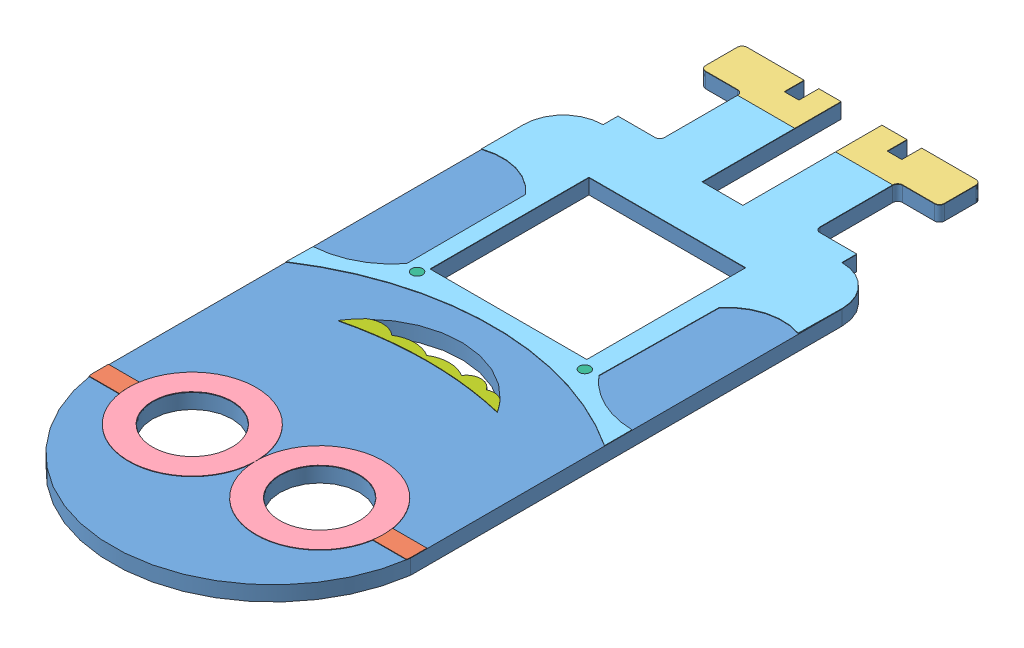
SolidWorks assembly Ensamblaje1, configuration Predeterminado. Lengths in mm.
Overall size (64.13 3.1 150.86).
7 component instances, 7 part files, 15 mates.
Components (placement in the parent):
- front-1: front [Predeterminado] at (-2.4657 43.7113 153.94) x (1 0 0) z (0 -1 0) size (64.13 150.86 3)
- band-1: band [Predeterminado] at (-62.549 43.8113 189.7256) x (1 0 0) z (0 -1 0) size (64.13 4 0.1)
- boots-1: boots [Predeterminado] at (-43.7181 43.8113 94.3) x (1 0 0) z (0 -1 0) size (48.08 9.33 0.1)
- eyes-1: eyes [Predeterminado] at (-37.429 43.7113 229.6833) x (1 0 0) z (0 1 0) size (51.31 25.65 0.1)
- jumpsuit-1: jumpsuit [Predeterminado] at (-44.951 43.8113 135.8861) x (1 0 0) z (0 -1 0) size (64.13 74.47 0.1)
- buttons-1: buttons [Predeterminado] at (-31.8965 43.8113 144.2405) x (1 0 0) z (0 -1 0) size (36.12 2.34 0.1)
- teeth-1: teeth [Predeterminado] at (-44.9051 43.8113 160.5398) x (1 0 0) z (0 -1 0) size (31.98 4.22 0.1)
Mates (geometry in assembly coordinates):
- Coincidente8: coincident: line of front-1 through (-41.4957 40.7113 214.3897) axis (0 1 0); line of band-1 through (-41.4957 43.7113 214.3897) axis (0 1 0)
- Coincidente10: coincident: plane of front-1 through (13.6183 43.7113 98.8397) normal (0 1 0); plane of band-1 through (-9.429 43.7113 209.9974) normal (0 -1 0)
- Coincidente11: coincident: plane of front-1 through (-41.4957 40.7113 127.5) normal (-1 0 0); plane of band-1 through (-41.4957 43.7113 211.0833) normal (-1 0 0)
- Coincidente13: coincident: plane of front-1 through (13.6183 43.7113 98.8397) normal (0 1 0); plane of boots-1 through (-43.7181 43.7113 94.3) normal (0 -1 0)
- Coincidente14: coincident: plane of front-1 through (-20.9913 40.7113 91.5) normal (0 0 -1); plane of boots-1 through (-43.7181 43.7113 91.5) normal (0 0 -1)
- Coincidente15: coincident: plane of front-1 through (-33.4696 40.7113 92.5) normal (-1 0 0); plane of boots-1 through (-33.4696 43.7113 94.3) normal (-1 0 0)
- Coincidente16: coincident: plane of front-1 through (13.6183 43.7113 98.8397) normal (0 1 0); plane of eyes-1 through (-37.429 43.7113 229.6833) normal (0 -1 0)
- Concéntrica1: concentric: cylinder of band-1 through (-22.6084 43.7113 213.0833) axis (0 1 0) radius 12.8267; cylinder of eyes-1 through (-22.6084 43.8113 213.0833) axis (0 -1 0) radius 12.8267
- Coincidente17: coincident: plane of front-1 through (13.6183 43.7113 98.8397) normal (0 1 0); plane of jumpsuit-1 through (-44.951 43.7113 135.8861) normal (0 -1 0)
- Coincidente21: coincident: plane of boots-1 through (-43.7181 43.7113 100.833) normal (0 0 1); plane of jumpsuit-1 through (-44.951 43.7113 100.833) normal (0 0 -1)
- Coincidente22: coincident: plane of front-1 through (22.6377 40.7113 214.3897) normal (1 0 0); plane of jumpsuit-1 through (22.6377 43.7113 135.8861) normal (1 0 0)
- Coincidente24: coincident: plane of front-1 through (13.6183 43.7113 98.8397) normal (0 1 0); plane of buttons-1 through (7.3558 43.7113 164.0044) normal (0 -1 0)
- Coincidente26: coincident: circle of jumpsuit-1; circle of buttons-1
- Coincidente27: coincident: plane of front-1 through (13.6183 43.7113 98.8397) normal (0 1 0); plane of teeth-1 through (-9.5738 43.7113 176.4848) normal (0 -1 0)
- Coincidente30: coincident: circle of front-1; circle of teeth-1
